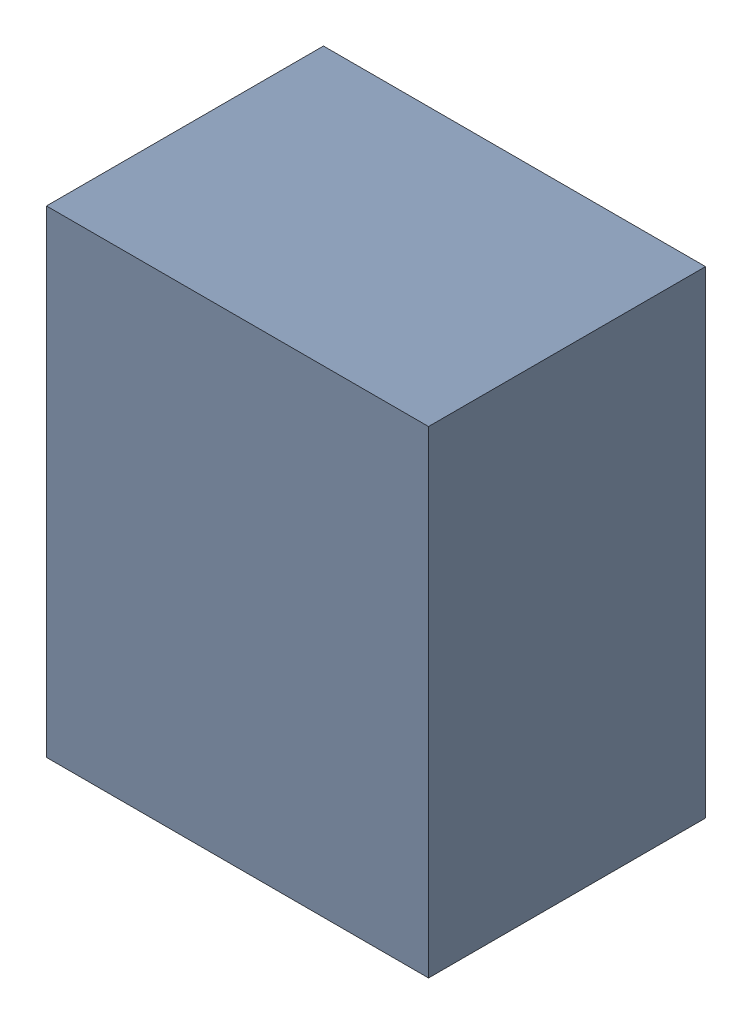
SolidWorks assembly U31, configuration Default. Lengths in mm.
Overall size (0.8 1 0.58).
2 component instances, 1 part files, 0 mates.
Components (placement in the parent):
- 836751984-1: 836751984 [Default] at (133.05 73.65 0.5) size (0.8 1 0.58)
  - Extruded_32-1: Extruded_32 [Default] at origin size (0.8 1 0.58)
